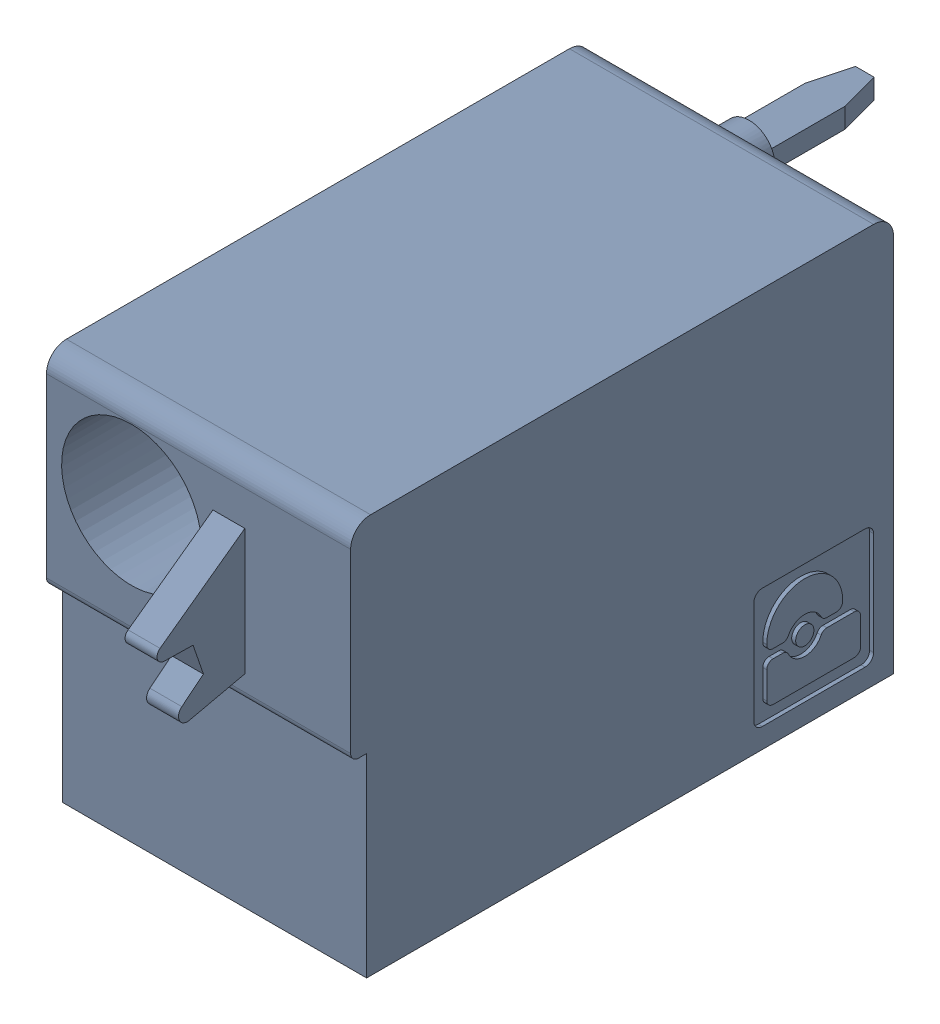
SolidWorks assembly J44, configuration Default. Lengths in mm.
Overall size (7.62 10 19.2).
2 component instances, 1 part files, 0 mates.
Components (placement in the parent):
- 1790487-1: 1790487 [Default] at (114.705 -15.67 -10.6) x (0 1 0) z (1 0 0) size (10 19.2 7.62)
  - ffkdsa1-v2-7.62-1: ffkdsa1-v2-7.62 [Default] at (-15.6914 -27.508 9.12) x (0 -1 0) z (0 0 1) size (19.2 10 7.62)
